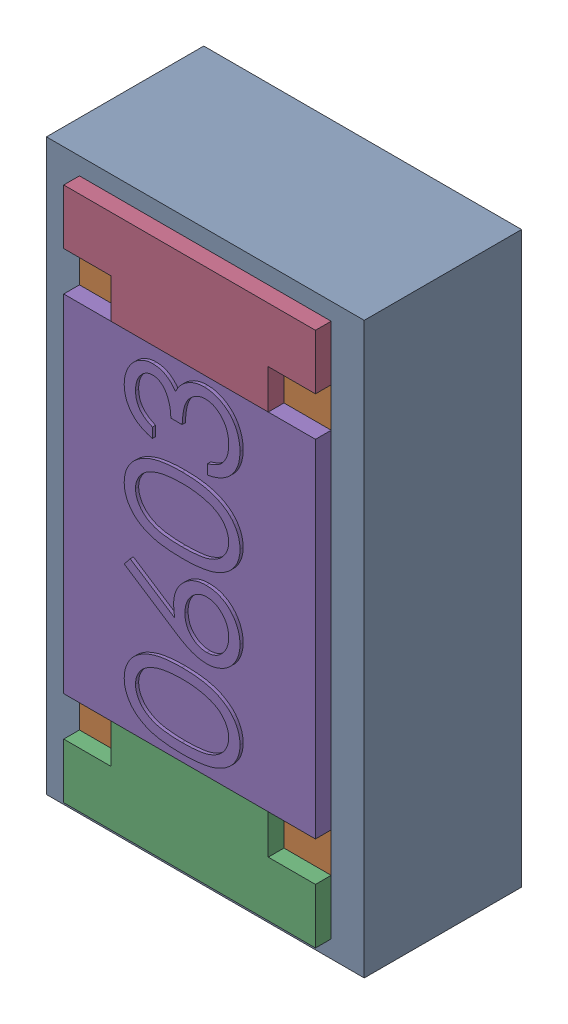
SolidWorks assembly SB7, configuration Default. Lengths in mm.
Overall size (1.01 1.81 0.56).
3 component instances, 2 part files, 0 mates.
Components (placement in the parent):
- 1088884704-1: 1088884704 [Default] at (3.3 12.775 0) size (1.01 1.81 0.5)
  - Extruded-0-1: Extruded-0 [Default] at origin size (1.01 1.81 0.5)
- R0603-1: R0603 [Default] at (3.2999 12.7751 0) x (0 1 0) z (1 0 0) size (1.7 0.56 0.8)
